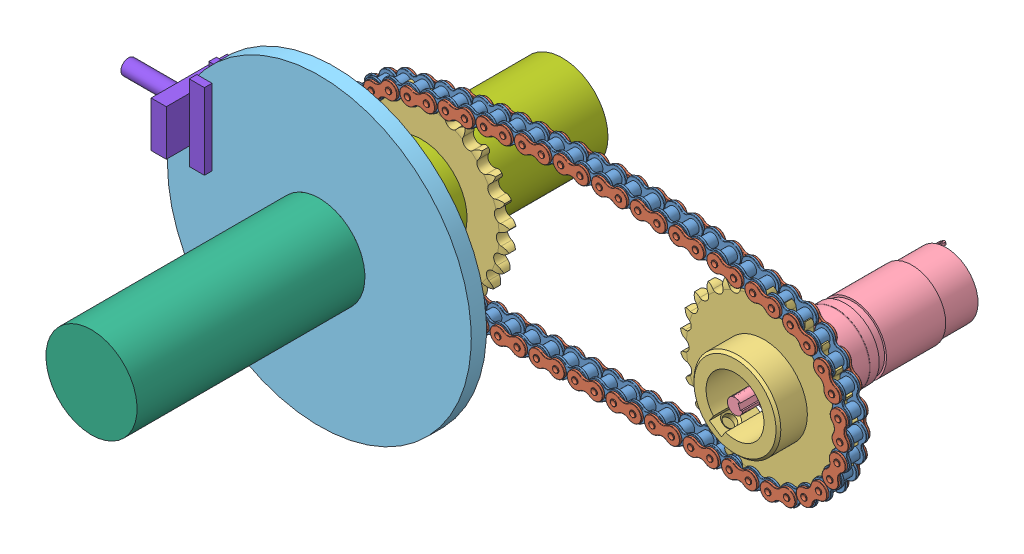
SolidWorks assembly Assem1, configuration Default. Lengths in mm.
Overall size (434.34 200 344.19).
13 component instances, 8 part files, 1 mates.
Components (placement in the parent):
- Assem 2-1: Assem 2 [Default] at (-205.347 -379.197 -593.5796) size (403.81 200 344.19)
  - chain drive and dc motor-1: chain drive and dc motor [Default] at (729.7386 963.1257 280.6982) x (-1 0 0) z (0 0 1) size (376.19 156.56 146)
    - Chain Drive-1: Chain Drive [Default] at (171.0759 206.2614 266.5858) size (376.19 156.56 30.44)
      - Chain A-1: Chain A [Default] at (-3.9373 5.8722 -1.9118) size (345.06 131.12 15.57)
        - Inner Chain-1: Inner Chain [Default] at (120.3815 217.874 272.3658) size (345.06 131.12 11.1)
        - Outer Chain-1: Outer Chain [Default] at (158.3912 217.874 270.6371) size (343.48 129.27 15.57)
      - Sprocket-1: Sprocket [Default] at (14.8599 170.457 272.397) x (0.831249 -0.555901 0) z (0 0 1) size (113.36 112.54 26.52)
      - Sprocket-2: Sprocket [Default] at (240.2692 170.457 272.397) x (0.94097 0.33849 0) z (0 0 1) size (113.36 112.54 26.52)
    - DC Motor-1: DC Motor [Default] at (185.9358 376.7184 426.2464) x (0.931343 0.364143 0) z (0.364143 -0.931343 0) size (45 146.01 45)
  - Disc-1: Disc [Default] at (318.3935 586.4073 884.134) size (200 200 10)
  - Shaft 1-1: Shaft 1 [Default] at (319.3555 591.3138 969.134) x (0 0 -1) z (0.981316 -0.192405 0) size (150 60 60)
  - Shaft 2-1: Shaft 2 [Default] at (316.4979 591.034 809.134) x (0 0 1) z (-0.92535 -0.379114 0) size (150 60 60)
- Magnetic holder-1: Magnetic holder [Default] at (35.2891 280.6997 317.3355) x (-1 0 0) z (0 -1 0) size (69.88 50 53.48)
Mates (geometry in assembly coordinates):
- Coincident1: coincident: plane of assembly; line of assembly; plane of Assem 2-1/Disc-1 through (113.0465 207.2102 300.5543) normal (0 0 1); line of Magnetic holder-1 through (42.3962 267.4178 300.5543) axis (0 -1 0)
